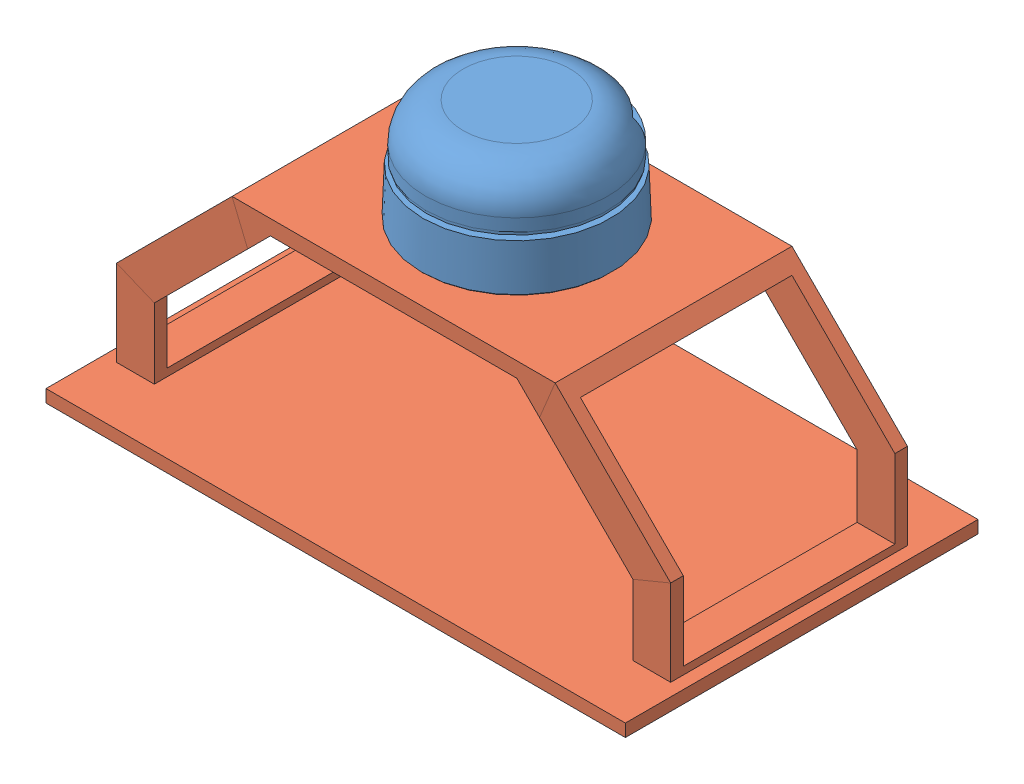
SolidWorks assembly Assem1, configuration Défaut. Lengths in mm.
Overall size (230 125.8 140).
2 component instances, 2 part files, 1 mates.
Components (placement in the parent):
- LIDAR-1: LIDAR [Default] at origin size (75.7 40.8 75.7)
- Plate-with-spaces-1: Plate-with-spaces [Défaut] at (0.0396 -80 1.924) x (1 0 0) z (0 -1 0) size (230 140 85)
Mates (geometry in assembly coordinates):
- Coincident1: coincident anti-aligned: plane of LIDAR-1 through (0 0 0) normal (0 -1 0); plane of Plate-with-spaces-1 through (-64.6167 0 48.924) normal (0 1 0)
